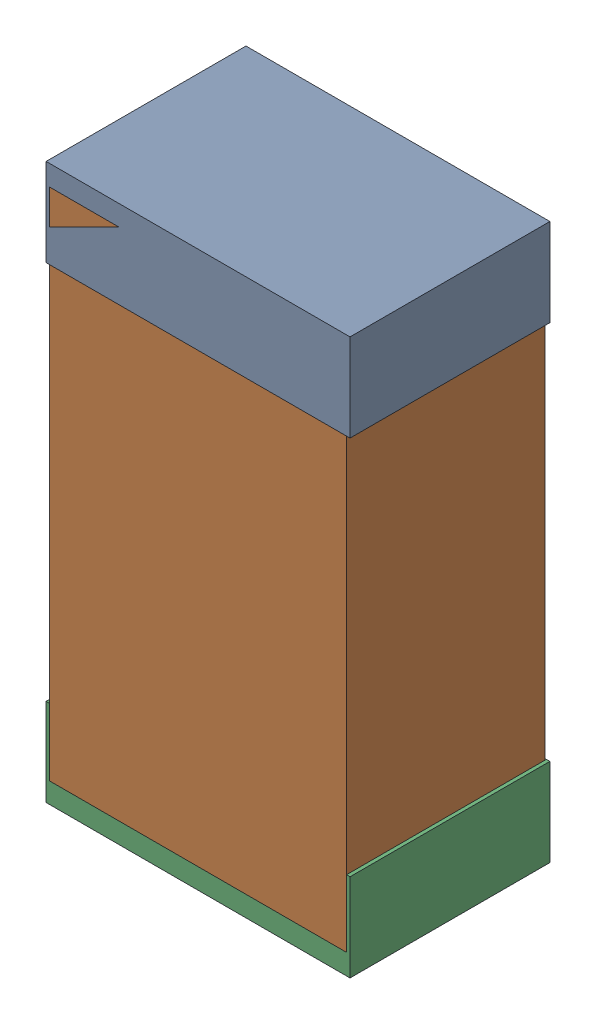
SolidWorks assembly R13Kanaloa_v2.0.0_Motor, configuration Default. Lengths in mm.
Overall size (1.3 2.38 0.85).
6 component instances, 2 part files, 0 mates.
Components (placement in the parent):
- 330415056-1: 330415056 [Default] at (41.656 67.294 -1.9574) size (1.3 0.38 0.85)
  - Extruded_2-1: Extruded_2 [Default] at origin size (1.3 0.38 0.85)
- 334787376-1: 334787376 [Default] at (41.656 66.294 -1.9524) size (1.27 2.2 0.85)
  - Extruded_16-1: Extruded_16 [Default] at origin size (1.27 2.2 0.85)
- 330415056-2: 330415056 [Default] at (41.656 65.294 -1.9574) size (1.3 0.38 0.85)
  - Extruded_2-1: Extruded_2 [Default] at origin size (1.3 0.38 0.85)
